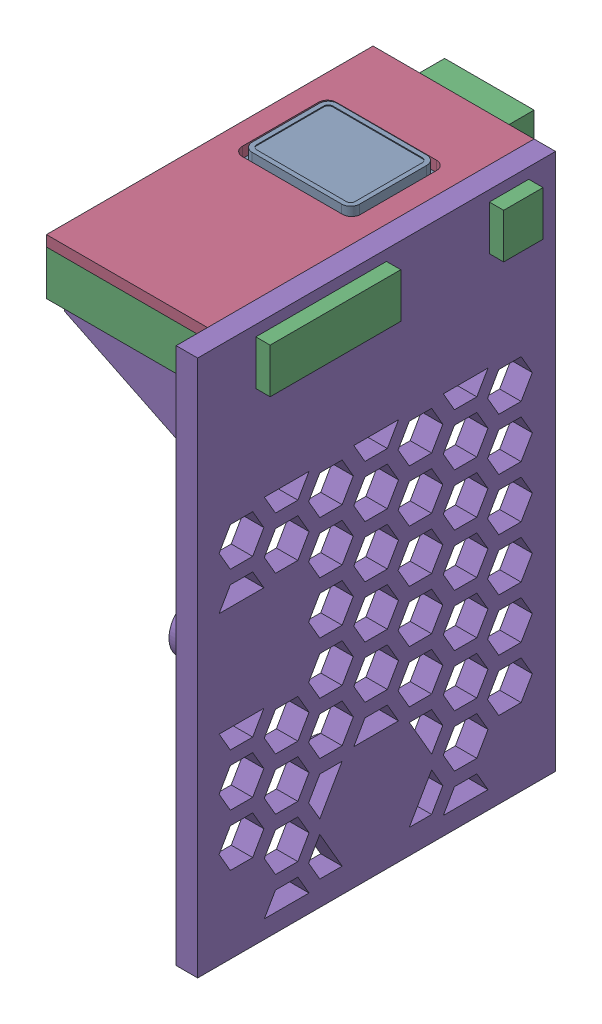
SolidWorks assembly power_button_assem, configuration Default. Lengths in mm.
Overall size (22 60.45 44).
5 component instances, 5 part files, 12 mates.
Components (placement in the parent):
- power_button-1: power_button [Default] at (-0.838 8.0709 12.9266) size (14 3.75 26)
- power_button_metal_piece-1: power_button_metal_piece [Default] at (9.2674 6.3209 -2.5734) x (0 0 1) z (1 0 0) size (32.5 1.9 9.5)
- power_button_back_support-1: power_button_back_support [Default] at (14.162 8.4209 31.9266) x (0 0 -1) z (1 0 0) size (40.5 5 22)
- power_button_front_support-1: power_button_front_support [Default] at (14.162 8.4209 31.9266) x (0 0 -1) z (1 0 0) size (36.5 5.2 18)
- daughterboard_bracket-1: daughterboard_bracket [Default] at (16.562 9.6209 45.4266) x (0 0 -1) z (0 1 0) size (40 18.4 60)
Mates (geometry in assembly coordinates):
- Coincident1: coincident anti-aligned: plane of power_button-1 through (-0.838 6.3209 12.9266) normal (0 -1 0); plane of power_button_metal_piece-1 through (-0.238 6.3209 -1.0734) normal (0 1 0)
- Distance1: distance = 0 mm aligned: plane of power_button-1 through (-1.838 7.5709 13.9266) normal (-1 0 0); plane of power_button_metal_piece-1 through (-1.838 6.0209 3.9266) normal (-1 0 0)
- Distance2: distance = 2 mm aligned: plane of power_button_back_support-1 through (14.162 3.4209 31.9266) normal (0 0 1); plane of power_button_metal_piece-1 through (6.462 6.0209 29.9266) normal (0 0 1)
- Distance3: distance = 2 mm aligned: plane of power_button_metal_piece-1 through (-1.838 6.0209 3.9266) normal (-1 0 0); plane of power_button_back_support-1 through (-3.838 3.4209 31.9266) normal (-1 0 0)
- Coincident5: coincident anti-aligned: plane of power_button_metal_piece-1 through (-0.238 6.0209 -1.0734) normal (0 -1 0); plane of power_button_back_support-1 through (14.162 6.0209 31.9266) normal (0 1 0)
- Distance4: distance = 6 mm anti-aligned: plane of power_button-1 through (-0.838 10.0709 3.4266) normal (0 0 -1); plane of power_button_back_support-1 through (-1.838 6.0209 -2.5734) normal (0 0 1)
- Coincident7: coincident anti-aligned: plane of power_button_back_support-1 through (14.162 4.4209 31.9266) normal (0 1 0); plane of power_button_front_support-1 through (14.162 4.4209 31.9266) normal (0 -1 0)
- Coincident8: coincident anti-aligned: plane of power_button_back_support-1 through (12.162 6.0209 29.9266) normal (-1 0 0); plane of power_button_front_support-1 through (12.162 4.4209 29.9266) normal (1 0 0)
- Coincident9: coincident anti-aligned: plane of power_button_back_support-1 through (-1.838 6.0209 29.9266) normal (0 0 -1); plane of power_button_front_support-1 through (12.162 4.4209 29.9266) normal (0 0 1)
- Coincident10: coincident anti-aligned: plane of power_button_back_support-1 through (14.162 8.4209 31.9266) normal (0 1 0); plane of daughterboard_bracket-1 through (16.563 8.4209 28.9266) normal (0 -1 0)
- Coincident11: coincident anti-aligned: plane of power_button_front_support-1 through (14.162 9.6209 31.9266) normal (1 0 0); plane of daughterboard_bracket-1 through (14.162 9.6209 45.4266) normal (-1 0 0)
- Coincident12: coincident anti-aligned: plane of power_button_back_support-1 through (18.162 8.4209 14.3266) normal (0 0 -1); plane of daughterboard_bracket-1 through (16.563 3.4209 14.3266) normal (0 0 1)
